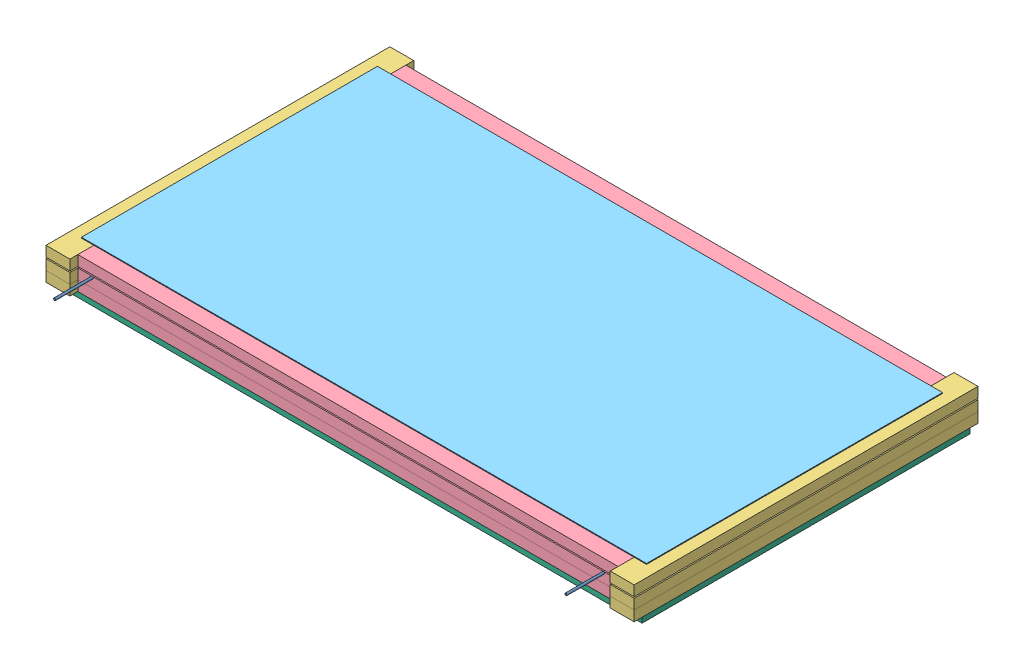
SolidWorks assembly solar_collector, configuration Default. Lengths in mm.
Overall size (2185.74 141.11 1388.9).
16 component instances, 6 part files, 45 mates.
Components (placement in the parent):
- serpentine_manifold-1: serpentine_manifold [Default] at (-0.0012 0 0) size (1907.94 7.94 1253.97)
- absorber-1: absorber [Default] at (-0.0012 3.9688 0) size (2100 4.76 1100)
- 2x4in_width-1: 2x4in_width [Default] at (-1048.42 3.9688 0) size (88.9 38.1 1277.8)
- 2x4in_width-4: 2x4in_width [Default] at (-1048.42 46.8312 0) size (88.9 38.1 1277.8)
- 2x4in_width-16: 2x4in_width [Default] at (1048.4175 8.7312 0) x (-1 0 0) z (0 0 1) size (88.9 38.1 1277.8)
- 2x4in_width-19: 2x4in_width [Default] at (1048.4175 -34.1313 0) x (-1 0 0) z (0 0 1) size (88.9 38.1 1277.8)
- 2x4in_width-20: 2x4in_width [Default] at (1048.4175 -34.1313 0) size (88.9 38.1 1277.8)
- 2x4in_width-21: 2x4in_width [Default] at (-1048.42 -34.1313 0) size (88.9 38.1 1277.8)
- 2x4in_length-20: 2x4in_length [Default] at (-0.0012 3.9688 -565.15) x (0 0 1) z (-1 0 0) size (88.9 38.1 2007.94)
- 2x4in_length-21: 2x4in_length [Default] at (-0.0012 46.8312 -565.15) x (0 0 1) z (-1 0 0) size (88.9 38.1 2007.94)
- 2x4in_length-22: 2x4in_length [Default] at (-0.0012 3.9688 565.15) x (0 0 -1) z (1 0 0) size (88.9 38.1 2007.94)
- 2x4in_length-23: 2x4in_length [Default] at (-0.0012 46.8312 565.15) x (0 0 1) z (-1 0 0) size (88.9 38.1 2007.94)
- 2x4in_length-24: 2x4in_length [Default] at (-0.0012 -34.1313 565.15) x (0 0 1) z (-1 0 0) size (88.9 38.1 2007.94)
- 2x4in_length-26: 2x4in_length [Default] at (-0.0012 -34.1313 -565.15) x (0 0 1) z (-1 0 0) size (88.9 38.1 2007.94)
- glass-1: glass [Default] at (-0.0012 46.8312 0) x (0 0 1) z (-1 0 0) size (1100 3 2100)
- 4x8ft_plywood_board-1: 4x8ft_plywood_board [Default] at (0 -91.2812 0) size (2185.74 19.05 1219.2)
Mates (geometry in assembly coordinates):
- Tangent2: tangent anti-aligned: cylinder of serpentine_manifold-1 through (-950.0012 0 750) axis (0 0 -1) radius 3.9688; plane of absorber-1 through (-0.0012 3.9688 0) normal (0 -1 0)
- Tangent3: tangent anti-aligned: cylinder of serpentine_manifold-1 through (949.9988 0 -450) axis (0 0 1) radius 3.9688; plane of absorber-1 through (-0.0012 3.9688 0) normal (0 -1 0)
- Coincident62: coincident anti-aligned: plane of 2x4in_length-24 through (-1003.97 -72.2313 609.6) normal (0 -1 0); plane of 4x8ft_plywood_board-1 through (0 -72.2313 0) normal (0 1 0)
- Coincident63: coincident aligned: line of 2x4in_length-24 through (-1003.97 -72.2313 609.6) axis (1 0 0); line of 4x8ft_plywood_board-1 through (-1092.87 -72.2313 609.6) axis (1 0 0)
- Coincident64: coincident anti-aligned: plane of 2x4in_width-21 through (-1003.97 -34.1313 638.9) normal (1 0 0); plane of 2x4in_length-24 through (-1003.97 -34.1313 565.15) normal (-1 0 0)
- Coincident65: coincident anti-aligned: line of 2x4in_width-21 through (-1092.87 -72.2313 638.9) axis (0 0 -1); line of 4x8ft_plywood_board-1 through (-1092.87 -72.2313 -609.6) axis (0 0 1)
- Coincident69: coincident anti-aligned: plane of 2x4in_width-20 through (1003.9675 -72.2313 638.9) normal (-1 0 0); plane of 2x4in_length-24 through (1003.9675 -34.1313 565.15) normal (1 0 0)
- Coincident70: coincident anti-aligned: plane of 2x4in_width-20 through (1092.8675 -72.2313 638.9) normal (0 -1 0); plane of 4x8ft_plywood_board-1 through (0 -72.2313 0) normal (0 1 0)
- Coincident71: coincident anti-aligned: plane of 2x4in_width-20 through (1003.9675 -72.2313 638.9) normal (-1 0 0); plane of 2x4in_length-26 through (1003.9675 -34.1313 -565.15) normal (1 0 0)
- Coincident72: coincident anti-aligned: line of 2x4in_length-26 through (-1003.97 -72.2313 -609.6) axis (1 0 0); line of 4x8ft_plywood_board-1 through (1092.87 -72.2313 -609.6) axis (-1 0 0)
- Coincident74: coincident anti-aligned: plane of 2x4in_length-26 through (-1003.97 -72.2313 -520.7) normal (0 -1 0); plane of 4x8ft_plywood_board-1 through (0 -72.2313 0) normal (0 1 0)
- Symmetric2: symmetric aligned: plane of 2x4in_width-20 through (1048.4175 -34.1313 638.9) normal (0 0 1); plane of 2x4in_width-20 through (1048.4175 -34.1313 -638.9) normal (0 0 -1)
- Symmetric3: symmetric aligned: plane of 2x4in_width-21 through (-1048.42 -34.1313 638.9) normal (0 0 1); plane of 2x4in_width-21 through (-1048.42 -34.1313 -638.9) normal (0 0 -1)
- Coincident75: coincident aligned: plane of 2x4in_width-1 through (-1048.42 3.9688 638.9) normal (0 0 1); plane of 2x4in_width-21 through (-1048.42 -34.1313 638.9) normal (0 0 1)
- Coincident76: coincident anti-aligned: plane of 2x4in_width-1 through (-1003.97 -34.1313 638.9) normal (0 -1 0); plane of 2x4in_width-21 through (-1092.87 -34.1313 638.9) normal (0 1 0)
- Coincident77: coincident aligned: plane of 2x4in_width-1 through (-1092.87 -34.1313 638.9) normal (-1 0 0); plane of 2x4in_width-21 through (-1092.87 -72.2313 638.9) normal (-1 0 0)
- Coincident80: coincident anti-aligned: plane of 2x4in_length-22 through (1003.9675 -34.1313 520.7) normal (0 -1 0); plane of 2x4in_length-24 through (-1003.97 -34.1313 520.7) normal (0 1 0)
- Coincident82: coincident anti-aligned: line of 2x4in_length-22 through (1003.9675 -34.1313 609.6) axis (-1 0 0); line of 2x4in_length-24 through (-1003.97 -34.1313 609.6) axis (1 0 0)
- Coincident83: coincident anti-aligned: plane of 2x4in_width-1 through (-1003.97 3.9688 638.9) normal (1 0 0); plane of 2x4in_length-22 through (-1003.97 3.9688 565.15) normal (-1 0 0)
- Coincident84: coincident anti-aligned: plane of 2x4in_length-20 through (-1003.97 -34.1313 -520.7) normal (0 -1 0); plane of 2x4in_length-26 through (-1003.97 -34.1313 -609.6) normal (0 1 0)
- Coincident85: coincident aligned: line of 2x4in_length-20 through (-1003.97 -34.1313 -609.6) axis (1 0 0); line of 2x4in_length-26 through (-1003.97 -34.1313 -609.6) axis (1 0 0)
- Coincident87: coincident anti-aligned: plane of 2x4in_width-19 through (1003.9675 -34.1313 638.9) normal (-1 0 0); plane of 2x4in_length-20 through (1003.9675 3.9688 -565.15) normal (1 0 0)
- Coincident88: coincident anti-aligned: plane of 2x4in_width-19 through (1092.8675 -34.1313 638.9) normal (0 -1 0); plane of 2x4in_width-20 through (1003.9675 -34.1313 638.9) normal (0 1 0)
- Coincident89: coincident aligned: line of 2x4in_width-19 through (1092.8675 -34.1313 638.9) axis (0 0 -1); line of 2x4in_width-20 through (1092.8675 -34.1313 638.9) axis (0 0 -1)
- Coincident90: coincident aligned: plane of 2x4in_width-19 through (1048.4175 -34.1313 -638.9) normal (0 0 -1); plane of 2x4in_width-20 through (1048.4175 -34.1313 -638.9) normal (0 0 -1)
- Symmetric4: symmetric aligned: plane of serpentine_manifold-1 through (-0.0012 0 0) normal (1 0 0); plane of absorber-1 through (-1050.0012 8.7312 -550) normal (-1 0 0); plane of absorber-1 through (1049.9988 8.7312 -550) normal (1 0 0)
- Symmetric5: symmetric aligned: plane of serpentine_manifold-1 through (-0.0012 0 0) normal (0 0 1); plane of absorber-1 through (-1050.0012 8.7312 -550) normal (0 0 -1); plane of absorber-1 through (-1050.0012 8.7312 550) normal (0 0 1)
- Coincident91: coincident anti-aligned: plane of absorber-1 through (-0.0012 3.9688 0) normal (0 -1 0); plane of 2x4in_width-1 through (-1092.87 3.9688 638.9) normal (0 1 0)
- Symmetric6: symmetric aligned: plane of absorber-1 through (-0.0012 3.9688 0) normal (1 0 0); plane of 2x4in_width-19 through (1092.8675 3.9688 638.9) normal (1 0 0); plane of 2x4in_width-1 through (-1092.87 -34.1313 638.9) normal (-1 0 0)
- Symmetric7: symmetric aligned: plane of absorber-1 through (-0.0012 3.9688 0) normal (0 0 1); plane of 2x4in_length-20 through (-1003.97 -34.1313 -609.6) normal (0 0 -1); plane of 2x4in_length-22 through (1003.9675 -34.1313 609.6) normal (0 0 1)
- Coincident92: coincident aligned: plane of 2x4in_width-1 through (-1048.42 3.9688 638.9) normal (0 0 1); plane of 2x4in_width-4 through (-1048.42 46.8312 638.9) normal (0 0 1)
- Coincident93: coincident anti-aligned: plane of absorber-1 through (-0.0012 8.7312 0) normal (0 1 0); plane of 2x4in_width-4 through (-1003.97 8.7312 638.9) normal (0 -1 0)
- Coincident94: coincident aligned: plane of 2x4in_width-1 through (-1092.87 -34.1313 638.9) normal (-1 0 0); plane of 2x4in_width-4 through (-1092.87 8.7312 638.9) normal (-1 0 0)
- Coincident95: coincident aligned: plane of 2x4in_width-16 through (1048.4175 8.7312 638.9) normal (0 0 1); plane of 2x4in_width-19 through (1048.4175 -34.1313 638.9) normal (0 0 1)
- Coincident96: coincident anti-aligned: plane of absorber-1 through (-0.0012 8.7312 0) normal (0 1 0); plane of 2x4in_width-16 through (1092.8675 8.7312 638.9) normal (0 -1 0)
- Coincident97: coincident aligned: plane of 2x4in_width-16 through (1092.8675 46.8312 638.9) normal (1 0 0); plane of 2x4in_width-19 through (1092.8675 3.9688 638.9) normal (1 0 0)
- Coincident98: coincident anti-aligned: plane of absorber-1 through (-0.0012 8.7312 0) normal (0 1 0); plane of 2x4in_length-21 through (-1003.97 8.7312 -520.7) normal (0 -1 0)
- Coincident99: coincident aligned: plane of 2x4in_length-20 through (-1003.97 -34.1313 -609.6) normal (0 0 -1); plane of 2x4in_length-21 through (-1003.97 8.7312 -609.6) normal (0 0 -1)
- Coincident100: coincident anti-aligned: plane of 2x4in_width-16 through (1003.9675 8.7312 638.9) normal (-1 0 0); plane of 2x4in_length-21 through (1003.9675 46.8312 -565.15) normal (1 0 0)
- Coincident101: coincident aligned: plane of 2x4in_length-22 through (1003.9675 -34.1313 609.6) normal (0 0 1); plane of 2x4in_length-23 through (-1003.97 46.8312 609.6) normal (0 0 1)
- Coincident102: coincident anti-aligned: plane of absorber-1 through (-0.0012 8.7312 0) normal (0 1 0); plane of 2x4in_length-23 through (-1003.97 8.7312 609.6) normal (0 -1 0)
- Coincident103: coincident anti-aligned: plane of 2x4in_width-4 through (-1003.97 46.8312 638.9) normal (1 0 0); plane of 2x4in_length-23 through (-1003.97 46.8312 565.15) normal (-1 0 0)
- Coincident104: coincident anti-aligned: plane of 2x4in_length-23 through (-1003.97 46.8312 520.7) normal (0 1 0); plane of glass-1 through (-0.0012 46.8312 0) normal (0 -1 0)
- Symmetric8: symmetric aligned: plane of absorber-1 through (-0.0012 3.9688 0) normal (0 0 1); plane of glass-1 through (-1050.0012 49.8312 550) normal (0 0 1); plane of glass-1 through (-1050.0012 49.8312 -550) normal (0 0 -1)
- Symmetric9: symmetric aligned: plane of absorber-1 through (-0.0012 3.9688 0) normal (1 0 0); plane of glass-1 through (-1050.0012 49.8312 -550) normal (-1 0 0); plane of glass-1 through (1049.9988 49.8312 -550) normal (1 0 0)
